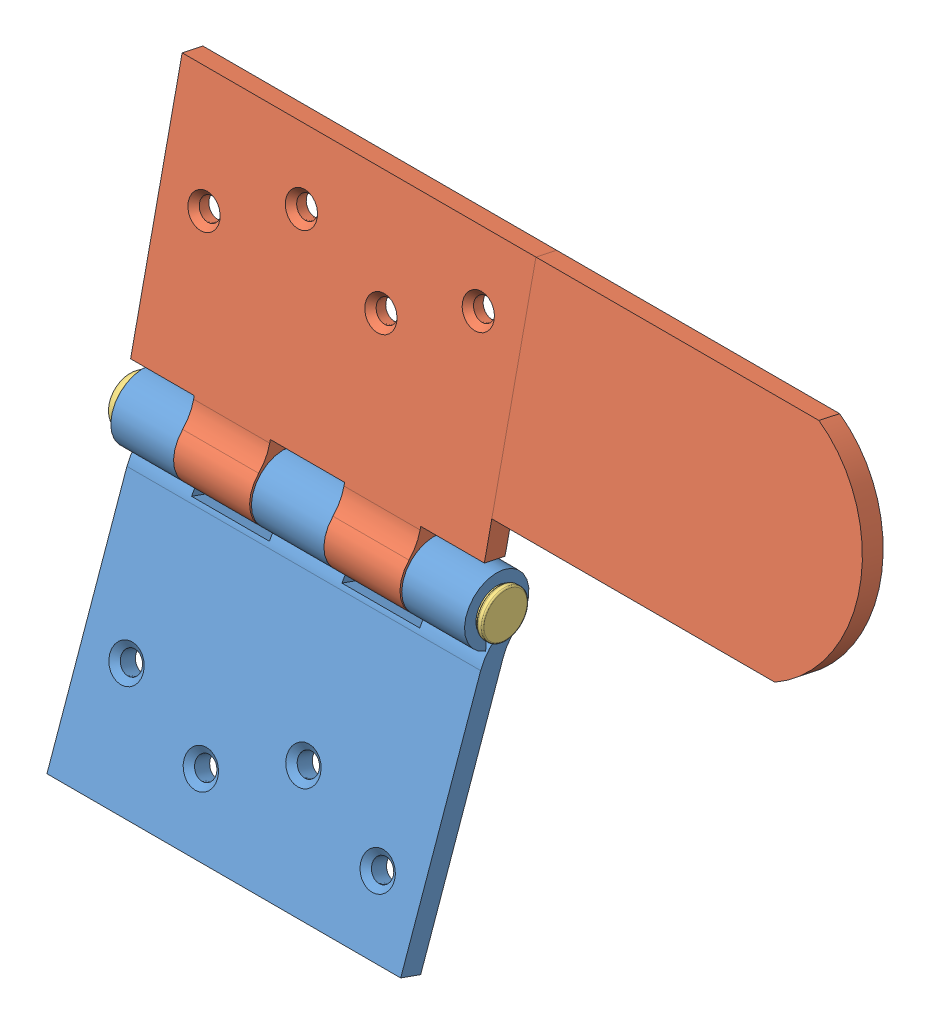
SolidWorks assembly BUTT HINGE, configuration Default. Lengths in mm.
Overall size (101.02 80.44 30.83).
3 component instances, 3 part files, 5 mates.
Components (placement in the parent):
- HINGE HALF A-1: HINGE HALF A [Default] at (94.7837 17.9742 83.296) x (0 -0.942832 0.333268) z (-1 0 0) size (45.16 9.11 50.13)
- HINGE HALF B-1: HINGE HALF B [Default] at (94.6587 17.9742 83.296) x (0 0.977557 -0.210672) z (-1 0 0) size (45.14 9.11 98.89)
- HINGE PIN-1: HINGE PIN [Default] at (67.5337 17.9742 83.296) size (53.5 7 7)
Mates (geometry in assembly coordinates):
- Concentric2: concentric anti-aligned: cylinder of HINGE HALF A-1 through (69.7837 17.9742 83.296) axis (1 0 0) radius 2.955; cylinder of HINGE PIN-1 through (120.0337 17.9742 83.296) axis (-1 0 0) radius 2.75
- Width3: width anti-aligned: plane of HINGE HALF A-1 through (69.7837 9.6839 79.9103) normal (-1 0 0); plane of HINGE PIN-1 through (119.7837 9.6839 79.9103) normal (1 0 0); plane of HINGE HALF A-1 through (69.5337 17.9742 83.296) normal (1 0 0); plane of HINGE PIN-1 through (120.0337 17.9742 83.296) normal (-1 0 0)
- Concentric3: concentric anti-aligned: cylinder of HINGE HALF A-1 through (69.7837 17.9742 83.296) axis (1 0 0) radius 2.955; cylinder of HINGE PIN-1 through (120.0337 17.9742 83.296) axis (-1 0 0) radius 2.75
- Concentric4: concentric anti-aligned: cylinder of HINGE HALF B-1 through (69.6587 17.9742 83.296) axis (1 0 0) radius 2.955; cylinder of HINGE PIN-1 through (120.0337 17.9742 83.296) axis (-1 0 0) radius 2.75
- Coincident1: coincident anti-aligned: plane of HINGE HALF A-1 through (78.6587 25.6308 86.9533) normal (1 0 0); plane of HINGE HALF B-1 through (78.6587 10.8449 78.6947) normal (-1 0 0)
